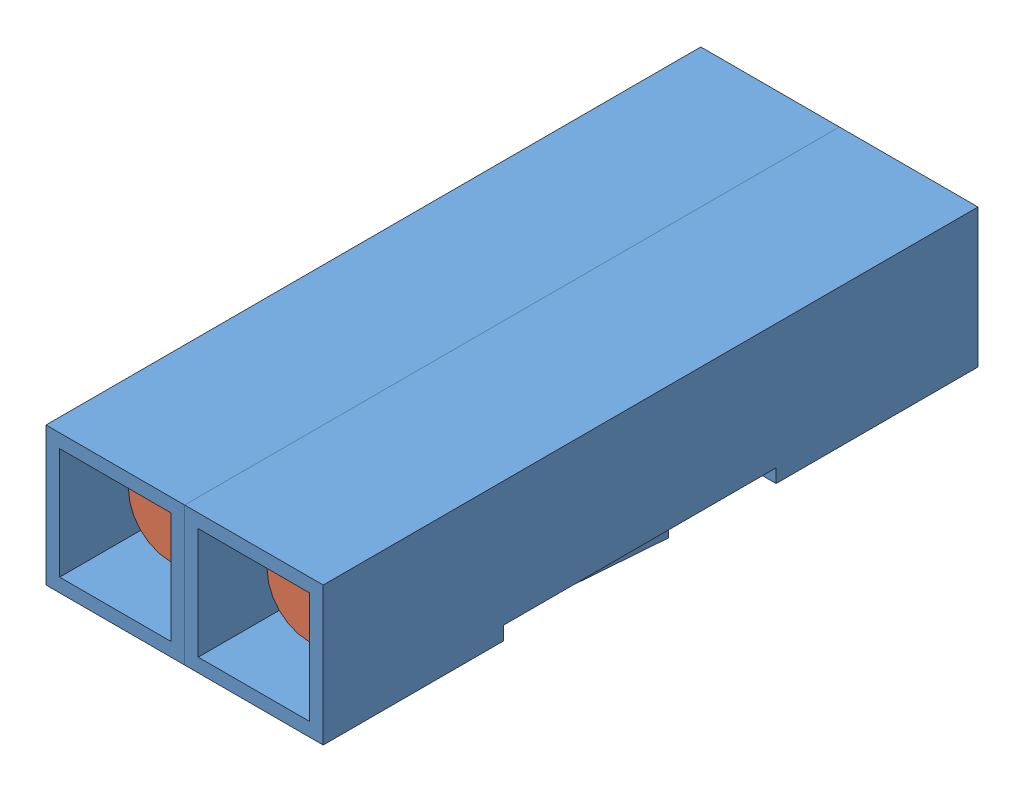
SolidWorks assembly DS1071 (BLS) Connector, configuration DS1071-1x2. Lengths in mm.
Overall size (5.08 2.79 12).
4 component instances, 2 part files, 3 mates.
Components (placement in the parent):
- TJC8 type^DS1071 (BLS) Connector-1: TJC8 type^DS1071 (BLS) Connector [Default] at origin (virtual)
- TJC8 type pin^DS1071 (BLS) Connector-1: TJC8 type pin^DS1071 (BLS) Connector [Default] at (0 0 0.5) x (-1 0 0) z (0 0 1) (virtual)
- TJC8 type pin^DS1071 (BLS) Connector-5: TJC8 type pin^DS1071 (BLS) Connector [Default] at (-2.54 0 0.5) x (-1 0 0) z (0 0 1) (virtual)
- TJC8 type^DS1071 (BLS) Connector-5: TJC8 type^DS1071 (BLS) Connector [Default] at (-2.54 0 0) (virtual)
Mates (geometry in assembly coordinates):
- Coincident1: coincident anti-aligned: plane of Copy of TJC8 type pin^DS1071 (BLS) Connector-1 through (0 0 0.5) normal (0 -1 0)
- Coincident2: coincident anti-aligned: plane of Copy of TJC8 type pin^DS1071 (BLS) Connector-1 through (0 0 0.5) normal (-1 0 0)
- Coincident3: coincident anti-aligned: plane of Copy of TJC8 type^DS1071 (BLS) Connector-1 through (0 0 0.5) normal (0 0 1); plane of TJC8 type pin-1 through (-0.625 0.575 0.5) normal (0 0 -1)
